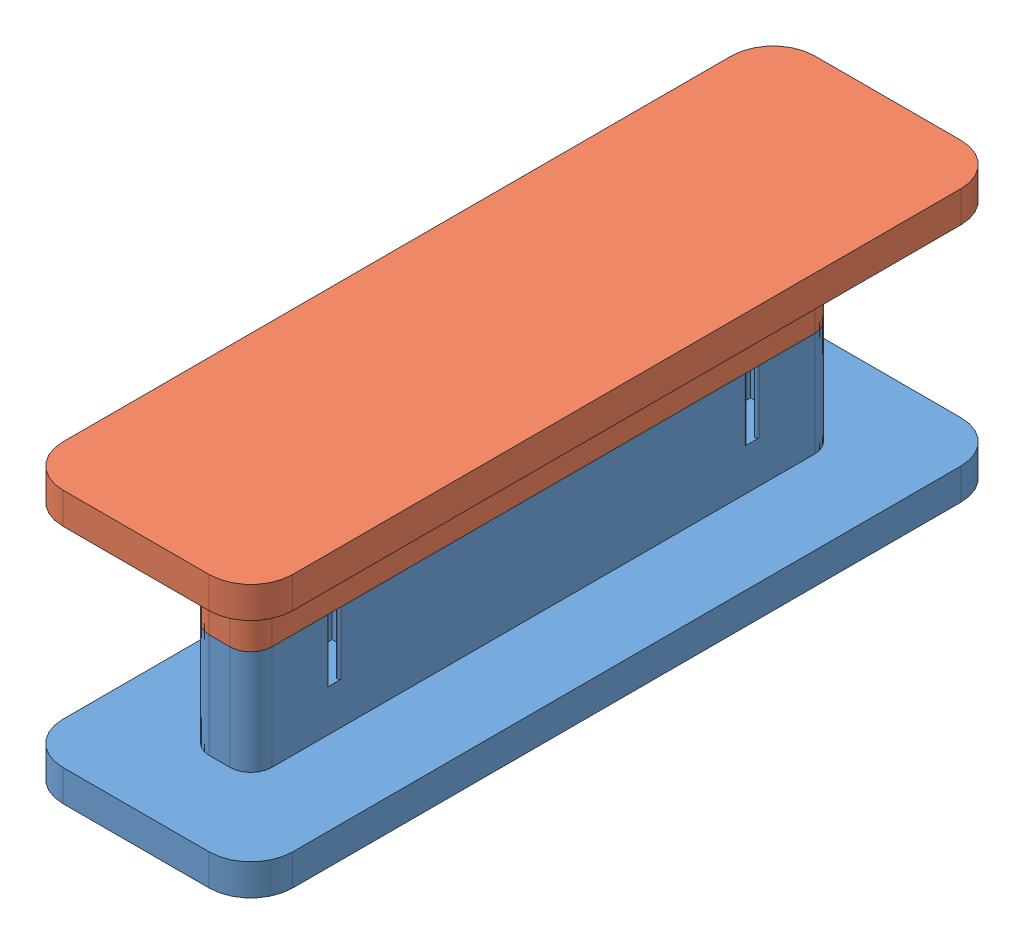
SolidWorks assembly coil core, configuration По умолчанию. Lengths in mm.
Overall size (11 13 36).
2 component instances, 2 part files, 3 mates.
Components (placement in the parent):
- coil core 2-2: coil core 2 [По умолчанию] at (1.5 -7.8228 30.3749) x (-1 0 0) z (0 0 1) size (11 6.5 36)
- coil core 1-1: coil core 1 [По умолчанию] at (1.5 -7.8228 30.3749) x (-1 0 0) z (0 0 1) size (11 9.4 36)
Mates (geometry in assembly coordinates):
- Расстояние1: distance = 0 mm aligned: plane of coil core 2-2 through (0 -17.8228 44.3749) normal (0 0 1); plane of coil core 1-1 through (0 -12.8228 44.3749) normal (0 0 1)
- Совпадение2: coincident aligned: plane of coil core 2-2 through (3 -17.8228 16.3749) normal (1 0 0); plane of coil core 1-1 through (3 -12.8228 16.3749) normal (1 0 0)
- Совпадение3: coincident anti-aligned: plane of coil core 2-2 through (1.5 -12.8228 30.3749) normal (0 1 0); plane of coil core 1-1 through (1.5 -12.8228 30.3749) normal (0 -1 0)
